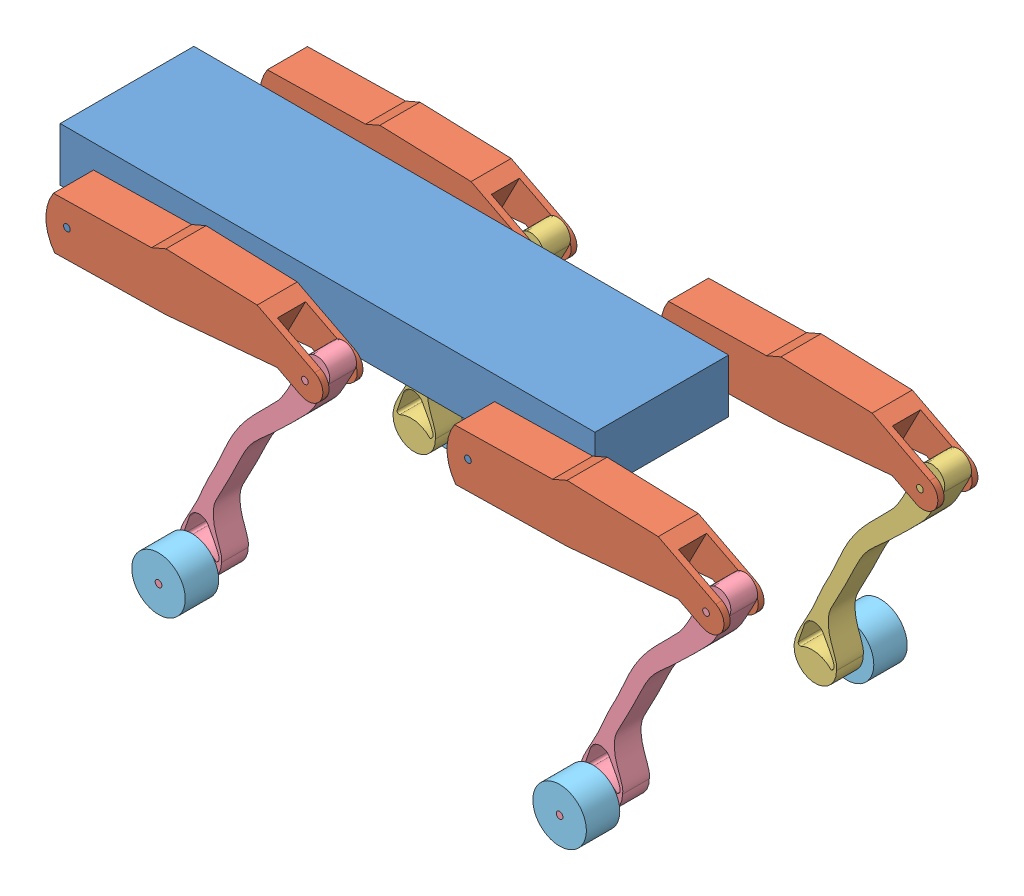
SolidWorks assembly rectangle_assembly, configuration Default. Lengths in mm.
Overall size (1083.34 429.4 480).
13 component instances, 5 part files, 16 mates.
Components (placement in the parent):
- body_part-1: body_part [Default] at origin size (800 80 380)
- upper_leg-1: upper_leg [Default] at (301.234 37.5713 30) size (414.38 91.5 60)
- upper_leg-2: upper_leg [Default] at (901.234 37.5713 30) size (414.38 91.5 60)
- upper_leg-3: upper_leg [Default] at (301.234 37.5713 -290) size (414.38 91.5 60)
- upper_leg-4: upper_leg [Default] at (901.234 37.5713 -290) size (414.38 91.5 60)
- bottom_R_leg_for_wheel-1: bottom_R_leg_for_wheel [Default] at (386.3271 -147.5254 -280) size (225.45 371.23 110)
- bottom_L_leg_for_wheel-1: bottom_L_leg_for_wheel [Default] at (386.3271 -147.5254 40) size (225.45 371.23 110)
- bottom_L_leg_for_wheel-2: bottom_L_leg_for_wheel [Default] at (986.3271 -147.5254 40) size (225.45 371.23 110)
- bottom_R_leg_for_wheel-2: bottom_R_leg_for_wheel [Default] at (986.3271 -147.5254 -280) size (225.45 371.23 110)
- wheel-4: wheel [Default] at (287.097 -302.6549 -340) size (80 80 50)
- wheel-5: wheel [Default] at (887.097 -302.6549 -340) size (80 80 50)
- wheel-6: wheel [Default] at (287.097 -302.6549 90) size (80 80 50)
- wheel-7: wheel [Default] at (887.097 -302.6549 90) size (80 80 50)
Mates (geometry in assembly coordinates):
- Coincident1: coincident aligned: circle of body_part-1; circle of upper_leg-1
- Coincident2: coincident aligned: circle of body_part-1; circle of upper_leg-2
- Coincident3: coincident aligned: circle of body_part-1; circle of upper_leg-4
- Coincident4: coincident aligned: circle of body_part-1; circle of upper_leg-3
- Coincident5: coincident aligned: circle of upper_leg-1; circle of bottom_L_leg_for_wheel-1
- Coincident6: coincident aligned: circle of upper_leg-2; circle of bottom_L_leg_for_wheel-2
- Coincident7: coincident aligned: circle of upper_leg-3; circle of bottom_R_leg_for_wheel-1
- Coincident8: coincident aligned: circle of upper_leg-4; circle of bottom_R_leg_for_wheel-2
- Coincident14: coincident aligned: circle of bottom_R_leg_for_wheel-1; circle of wheel-4
- Coincident15: coincident aligned: circle of bottom_L_leg_for_wheel-1; circle of wheel-6
- Coincident16: coincident aligned: circle of bottom_L_leg_for_wheel-2; circle of wheel-7
- Coincident17: coincident aligned: circle of bottom_R_leg_for_wheel-2; circle of wheel-5
- Parallel2: parallel aligned: plane of upper_leg-4 through (734.8579 37.6965 -230) normal (0 0 1); plane of bottom_R_leg_for_wheel-2 through (1056.1465 20.0575 -230) normal (0 0 1)
- Parallel3: parallel aligned: plane of upper_leg-2 through (734.8579 37.6965 30) normal (0 0 -1); plane of bottom_L_leg_for_wheel-2 through (1056.1465 20.0575 30) normal (0 0 -1)
- Parallel4: parallel aligned: plane of upper_leg-3 through (134.8579 37.6965 -230) normal (0 0 1); plane of bottom_R_leg_for_wheel-1 through (456.1465 20.0575 -230) normal (0 0 1)
- Parallel5: parallel aligned: plane of upper_leg-1 through (134.8579 37.6965 30) normal (0 0 -1); plane of bottom_L_leg_for_wheel-1 through (456.1465 20.0575 30) normal (0 0 -1)
